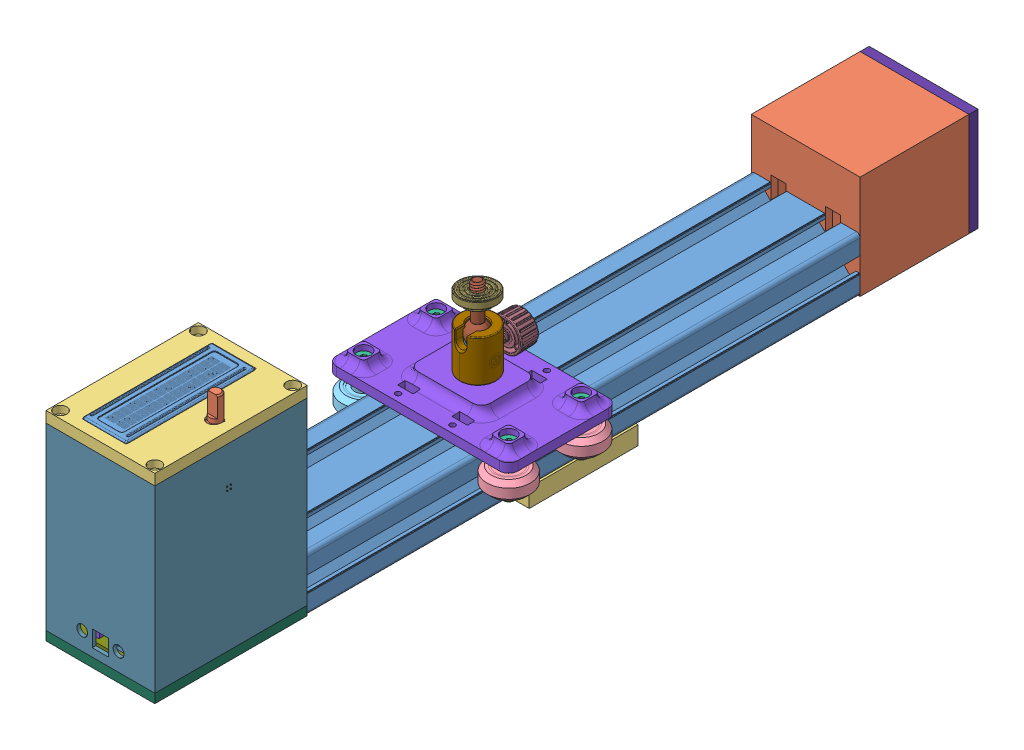
SolidWorks assembly SliderAssembly, configuration Default. Lengths in mm.
Overall size (108.85 134.98 465.23).
58 component instances, 39 part files, 105 mates.
Components (placement in the parent):
- 30x60AluminumExtrusion-1: 30x60AluminumExtrusion [Default] at (105.8219 168.111 384.4079) x (0 -1 0) z (0 0 -1) size (30 60 304.8)
- EndCover-1: EndCover [Default] at (105.8219 170.611 79.6079) x (0 -1 0) z (0 0 -1) size (57 60 60)
- TripodMount-1: TripodMount [Default] at (105.8219 143.111 232.0079) x (0 0 -1) z (0 1 0) size (60 60 10.68)
- VSlotGantryAssembly2-1: VSlotGantryAssembly2 [Default] at (68.2909 143.5962 146.6719) size (108.85 32 72.56)
  - V-Wheel Solid Wheel-1: V-Wheel Solid Wheel [Default] at (76.3282 31.8437 123.3877) x (-0.38895 0 -0.921259) z (-0.921259 0 0.38895) size (23.9 20 23.9)
  - V-Wheel Solid Wheel-2: V-Wheel Solid Wheel [Default] at (87.9897 31.8437 111.6656) x (0.696587 0 0.717472) z (0.717472 0 -0.696587) size (23.9 20 23.9)
  - V-Wheel Solid Wheel - spacer-1: V-Wheel Solid Wheel - spacer [Default] at (-15.7649 31.8437 95.6225) x (-1 0 0) z (0 0 1) size (23.9 17 23.9)
  - V-Wheel Solid Wheel - spacer-2: V-Wheel Solid Wheel - spacer [Default] at (-15.7649 29.8437 135.6225) x (-1 0 0) z (0 0 1) size (23.9 17 23.9)
  - M5x25 low profile screw-1: M5x25 low profile screw [Default] at (-0.4953 49.5148 98.6213) x (1 0 0) z (0 -1 0) size (11 11 27)
  - M5x25 low profile screw-2: M5x25 low profile screw [Default] at (-0.4953 49.5148 138.6213) x (1 0 0) z (0 -1 0) size (11 11 27)
  - M5x25 low profile screw-3: M5x25 low profile screw [Default] at (79.5047 49.5148 98.6213) x (0.999976 0 0.00694) z (0 -1 0) size (11 11 27)
  - M5x25 low profile screw-4: M5x25 low profile screw [Default] at (79.5047 49.5148 138.6213) x (0.999419 0 -0.034076) z (0 -1 0) size (11 11 27)
  - M5 Nylock-1: M5 Nylock [Default] at (-0.4953 25.5148 138.6213) x (-1 0 0) z (0 -1 0) size (8.02 9.26 5)
  - M5 Nylock-2: M5 Nylock [Default] at (-0.4953 27.5148 98.6213) x (-1 0 0) z (0 -1 0) size (8.02 9.26 5)
  - M5 Nylock-3: M5 Nylock [Default] at (79.5047 27.5148 98.6213) x (-1 0 0) z (0 -1 0) size (8.02 9.26 5)
  - M5 Nylock-4: M5 Nylock [Default] at (79.5047 27.5148 138.6213) x (-1 0 0) z (0 -1 0) size (8.02 9.26 5)
  - GantryPlatev2-1: GantryPlatev2 [Default] at (39.5047 42.5148 118.6213) x (-1 0 0) z (0 1 0) size (100 60 10)
- BallHead-1: BallHead [Default] at (109.5949 196.6884 264.1327) size (42.71 44.87 45.01)
  - Ball Head.IGS-1: Ball Head.IGS [Default] at origin size (42.71 44.87 45.01)
    - Gehäuse.IGS-1: Gehäuse.IGS [Default] at origin size (38.01 23.01 20.01)
    - Druckstück.IGS-1: Druckstück.IGS [Default] at (0 -0.5774 0) x (0.996351 0 0.085346) z (-0.085346 0 0.996351) size (23.21 15.61 12)
    - Kugelkopfschraube.IGS-1: Kugelkopfschraube.IGS [Default] at (0 18.5 0) x (0.937202 0.036262 -0.346898) z (0.344349 0.061981 0.936794) size (11.9 30.66 12.01)
    - Scheibe.IGS-1: Scheibe.IGS [Default] at (-0.7516 32.015 -0.6179) x (0.736904 0.071715 0.672182) z (-0.673717 -0.003682 0.73898) size (39.21 6.21 20)
    - Schraube.IGS-1: Schraube.IGS [Default] at (0 9.5 -14.9504) x (0 0 1) z (-0.999799 0.020029 0) size (21.11 18.19 33.94)
- Enclosurev1-5: Enclosurev1 [Default] at (135.8219 232.111 468.4079) x (-1 0 0) z (0 -1 0) size (60 84 99)
- BottomCover-4: BottomCover [Default] at (105.8219 153.111 426.4079) x (0 0 -1) z (0 1 0) size (84 60 5)
- PCB_Assembly-3: PCB_Assembly [Default] at (116.718 142.28 473.9554) x (-1 0 0) z (0 0 -1) size (50 25.86 70)
  - DummyPCB-1: DummyPCB [Default] at (10.8961 19.431 47.5475) x (1 0 0) z (0 -1 0) size (50 75 1.6)
  - ESP32_pinHeader-1: ESP32_pinHeader [Default] at (-11.8439 19.431 67.6769) size (48.76 8 2.5)
  - ESP32_pinHeader-2: ESP32_pinHeader [Default] at (-11.8439 19.431 44.6369) size (48.76 8 2.5)
  - ESP32-1: ESP32 [Default] at (10.8871 26.7106 55.5363) x (0 0 1) z (0 1 0) size (25.55 48.91 13.27)
  - Terminal_2-1: Terminal_2 [Default] at (1.706 19.431 17.5475) x (1 0 0) z (0 1 0) size (10.56 10 18.26)
  - Terminal_2-2: Terminal_2 [Default] at (-8.6851 19.431 17.5475) x (1 0 0) z (0 1 0) size (10.56 10 18.26)
  - PinHeader_5-1: PinHeader_5 [Default] at (-6.1448 19.431 34.2861) size (13.2 8 2.5)
  - PinHeader_2-1: PinHeader_2 [Default] at (8.9821 19.431 34.5153) size (5.58 8 2.5)
  - 0805_resistor-1: 0805_resistor [Default] at (13.7943 19.431 31.1443) size (2 0.6 1.25)
  - PinHeaderMale_4-1: PinHeaderMale_4 [Default] at (1.1821 19.177 37.574) x (-1 0 0) z (0 1 0) size (10.16 2.54 11.94)
  - PinHeaderMale_4-2: PinHeaderMale_4 [Default] at (12.0796 19.177 37.581) x (-1 0 0) z (0 1 0) size (10.16 2.54 11.94)
  - PinHeaderMale_3-1: PinHeaderMale_3 [Default] at (-6.4657 19.431 40.8233) x (1 0 0) z (0 1 0) size (7.62 2.54 11.94)
  - Capacitor2-1: Capacitor2 [Default] at (13.3886 19.421 26.2597) x (0 0 -1) z (0 1 0) size (8.5 8.12 14.12)
  - TMC2209_pinHeader2-1: TMC2209_pinHeader2 [Default] at (32.422 19.431 31.8475) x (0 0 -1) z (1 0 0) size (20.82 8 2.5)
  - TMC2209_pinHeader2-2: TMC2209_pinHeader2 [Default] at (19.722 19.431 31.8475) x (0 0 -1) z (1 0 0) size (20.82 8 2.5)
  - TMC2209-2: TMC2209 [Default] at (26.072 27.151 22.8475) x (0 0 1) z (0 1 0) size (20.6 15.43 22.6)
- BeltTensionerAssembly-2: BeltTensionerAssembly [Default] at (123.7274 141.4711 84.1198) x (-0.8441 0 0.536186) z (-0.536186 0 -0.8441) size (64.72 49 62.26)
  - SliderPlate-1: SliderPlate [Default] at (-6.0834 22.0445 41.5251) x (-0.8441 0 -0.536186) z (0 1 0) size (50 20 34)
  - BasePlate-2: BasePlate [Default] at (-6.7261 16.0445 42.537) x (0.8441 0 0.536186) z (0 1 0) size (50 40 6)
  - FrontFixed-2: FrontFixed [Default] at (-15.5732 22.0445 56.4646) x (0.8441 0 0.536186) z (0 1 0) size (50 42 11)
  - washer-1: washer [Default] at (-6.0834 50.0445 41.5251) x (0 0 1) z (0 -1 0) size (8 8 1)
  - washer-2: washer [Default] at (-6.0834 34.0445 41.5251) x (1 0 0) z (0 -1 0) size (8 8 1)
  - M5x25-1: M5x25 [Default] at (-6.0834 65.0445 41.5251) x (0 -1 0) z (0 0 1) size (35 7 7)
  - ideler-1: ideler [Default] at (-6.0834 49.0445 41.5251) x (0 -1 0) z (-1 0 0) size (15 32 32)
- endCover-connect-1: endCover-connect [Default] at (90.8219 168.111 79.6079) size (8.7 8.7 20)
- endCover-connect-2: endCover-connect [Default] at (120.8219 168.111 79.6079) x (-0.035719 0.999362 0) z (0 0 1) size (8.7 8.7 20)
- Logo-3: Logo [Default] at (105.8219 181.611 14.6079) size (60 57 6)
- Nema17-3: Nema17 [По умолчанию] at (105.9877 241.111 427.2351) x (-0.021334 0 0.999772) z (0.999772 0 0.021334) size (42.3 62 51.35)
- LCD-1: LCD [Default] at (101.4719 257.111 426.7579) x (0 0 1) z (-1 0 0) size (80.2 17.64 36)
- Rotary_Encoder-1: Rotary_Encoder [Default] at (129.8687 248.411 427.8198) x (-1 0 0) z (0 1 0) size (19 32 30)
- TopCover-5: TopCover [Default] at (105.8219 257.111 428.4079) x (0 0 -1) z (0 1 0) size (84 60 6)
Mates (geometry in assembly coordinates):
- Concentric1: concentric aligned: cylinder of Nema17-1 through (105.8219 169.111 424.4079) axis (0 1 0) radius 2.5; cylinder of GT2TimingPulley-1 through (105.8219 170.311 424.4079) axis (0 1 0) radius 2.5
- Coincident4: coincident aligned: plane of Nema17-1 through (105.8219 169.111 424.4079) normal (0 -1 0); plane of GT2TimingPulley-1 through (105.8219 169.111 424.4079) normal (0 -1 0)
- Distance7: distance = 0 mm anti-aligned: plane of VSlotGantryAssembly-1/80mm gantry plate-1 through (103.8719 183.111 236.703) normal (0 -1 0); plane of 30x60AluminumExtrusion-1 through (95.3219 183.111 79.6079) normal (0 1 0)
- Tangent1: tangent anti-aligned: plane of 30x60AluminumExtrusion-1 through (75.8219 181.079 79.6079) normal (-1 0 0); cylinder of VSlotGantryAssembly-1/V-Wheel Solid Wheel-2 through (63.8719 171.226 206.703) axis (0 -1 0) radius 11.95
- Tangent2: tangent anti-aligned: plane of 30x60AluminumExtrusion-1 through (75.8219 181.079 79.6079) normal (-1 0 0); cylinder of VSlotGantryAssembly-1/V-Wheel Solid Wheel-1 through (63.8719 171.226 266.703) axis (0 -1 0) radius 11.95
- Coincident30: coincident aligned: plane of 30x60AluminumExtrusion-1 through (75.8219 155.143 79.6079) normal (-1 0 0); plane of EndCover-1 through (75.8219 198.111 19.6079) normal (-1 0 0)
- Coincident31: coincident aligned: plane of 30x60AluminumExtrusion-1 through (95.3219 153.111 79.6079) normal (0 -1 0); plane of EndCover-1 through (135.8219 153.111 19.6079) normal (0 -1 0)
- Coincident32: coincident anti-aligned: plane of 30x60AluminumExtrusion-1 through (77.8539 181.079 79.6079) normal (0 0 -1); plane of EndCover-1 through (105.8219 170.611 79.6079) normal (0 0 1)
- Distance8: distance = 12.5 mm aligned: plane of Logo-1 through (57.6023 165.611 2.2147) normal (0 -1 0); plane of EndCover-1 through (135.8219 153.111 19.6079) normal (0 -1 0)
- Coincident37: coincident anti-aligned: plane of EndCover-1 through (131.5466 154.5156 77.6079) normal (0 1 0); plane of BeltTensionerAssembly-2/BasePlate-1 through (104.5466 154.5156 52.6079) normal (0 -1 0)
- Coincident38: coincident anti-aligned: plane of EndCover-1 through (105.8219 170.611 75.6079) normal (0 0 -1); plane of BeltTensionerAssembly-2/BasePlate-1 through (79.5466 154.5156 77.6079) normal (0 0 1)
- Distance9: distance = 5 mm anti-aligned: plane of BeltTensionerAssembly-2/BasePlate-1 through (129.5466 154.5156 27.6079) normal (1 0 0); plane of EndCover-1 through (134.5466 157.5156 77.6079) normal (-1 0 0)
- Tangent3: tangent anti-aligned: plane of ? through (103.8719 186.111 236.703) normal (0 1 0); face of ?
- Coincident47: coincident aligned: plane of 30x60AluminumExtrusion-1 through (75.8219 155.143 79.6079) normal (-1 0 0); plane of TripodMount-1 through (75.8219 153.111 262.0079) normal (-1 0 0)
- Coincident48: coincident anti-aligned: plane of 30x60AluminumExtrusion-1 through (95.3219 153.111 79.6079) normal (0 -1 0); plane of TripodMount-1 through (105.8219 153.111 232.0079) normal (0 1 0)
- Distance10: distance = 122.4 mm anti-aligned: plane of TripodMount-1 through (135.8219 153.111 202.0079) normal (0 0 -1); plane of EndCover-1 through (105.8219 170.611 79.6079) normal (0 0 1)
- Coincident50: coincident aligned: plane of 30x60AluminumExtrusion-1 through (135.8219 181.079 79.6079) normal (1 0 0); plane of Enclosurev1-3 through (135.8219 157.111 464.4079) normal (1 0 0)
- Concentric2: concentric aligned: cylinder of 30x60AluminumExtrusion-1 through (120.8219 168.111 79.6079) axis (0 0 1) radius 3.5; cylinder of Enclosurev1-3 through (120.8219 168.111 369.4079) axis (0 0 1) radius 3.5
- Coincident51: coincident anti-aligned: plane of 30x60AluminumExtrusion-1 through (77.8539 181.079 384.4079) normal (0 0 1); plane of Enclosurev1-3 through (135.8219 157.111 384.4079) normal (0 0 -1)
- Distance11: distance = 3 mm anti-aligned: plane of PCB_Assembly-1/DummyPCB-1 through (84.0424 153.111 395.4079) normal (0 -1 0); plane of BottomCover-1 through (132.8219 157.111 387.4079) normal (0 1 0)
- Distance12: distance = 5 mm aligned: plane of PCB_Assembly-1/DummyPCB-1 through (81.0424 153.111 459.4079) normal (-1 0 0); plane of BottomCover-1 through (55.8219 157.111 441.4079) normal (-1 0 0)
- Coincident56: coincident anti-aligned: plane of Enclosurev1-3 through (133.8219 239.111 462.4079) normal (0 0 -1); plane of PCB_Assembly-1/DummyPCB-1 through (128.0424 153.111 462.4079) normal (0 0 1)
- Coincident57: coincident aligned: plane of Enclosurev1-3 through (135.8219 239.111 464.4079) normal (0 1 0); plane of OLED-1 through (149.8219 227.611 435.6192) normal (0 1 0)
- Coincident58: coincident aligned: plane of Enclosurev1-3 through (135.8219 239.111 387.4079) normal (0 0 -1); plane of OLED-1 through (156.71 238.111 387.4079) normal (0 0 -1)
- Coincident60: coincident aligned: plane of Enclosurev1-3 through (135.8219 239.111 464.4079) normal (0 1 0); plane of OLED-2 through (149.8219 228.111 435.6192) normal (0 1 0)
- Coincident61: coincident anti-aligned: plane of Enclosurev1-3 through (162.8219 216.111 389.4079) normal (0 0 1); plane of OLED-2 through (145.023 238.111 389.4079) normal (0 0 -1)
- Coincident62: coincident aligned: circle of Enclosurev1-3; plane of Rotary_Encoder-2 through (154.746 237.111 450.1435) normal (0 1 0)
- Coincident63: coincident aligned: circle of Enclosurev1-3; plane of Rotary_Encoder-3 through (152.0684 237.111 430.2318) normal (0 1 0)
- Coincident64: coincident: plane of Enclosurev1-3 through (162.8219 239.111 444.4079) normal (-1 0 0); line of Rotary_Encoder-3 through (162.8219 223.286 438.5345) axis (0 0 -1)
- Coincident65: coincident aligned: plane of 30x60AluminumExtrusion-1 through (135.8219 181.079 79.6079) normal (1 0 0); plane of Enclosurev1-4 through (135.8219 153.111 464.4079) normal (1 0 0)
- Coincident66: coincident aligned: plane of 30x60AluminumExtrusion-1 through (125.3219 153.111 79.6079) normal (0 -1 0); plane of Enclosurev1-4 through (135.8219 153.111 464.4079) normal (0 -1 0)
- Coincident67: coincident anti-aligned: plane of 30x60AluminumExtrusion-1 through (77.8539 181.079 384.4079) normal (0 0 1); plane of Enclosurev1-4 through (135.8219 153.111 384.4079) normal (0 0 -1)
- Coincident68: coincident aligned: plane of Enclosurev1-4 through (135.8219 153.111 464.4079) normal (1 0 0); plane of TopCover-2 through (135.8219 231.111 461.4079) normal (1 0 0)
- Coincident69: coincident aligned: plane of Enclosurev1-4 through (135.8219 153.111 384.4079) normal (0 0 -1); plane of TopCover-2 through (78.8219 231.111 384.4079) normal (0 0 -1)
- Coincident70: coincident anti-aligned: plane of Enclosurev1-4 through (135.8219 231.111 464.4079) normal (0 1 0); plane of TopCover-2 through (78.8219 231.111 461.4079) normal (0 -1 0)
- Coincident71: coincident anti-aligned: plane of Nema17-1 through (105.8219 231.111 424.4079) normal (0 1 0); plane of TopCover-2 through (78.8219 231.111 461.4079) normal (0 -1 0)
- Concentric4: concentric anti-aligned: circle of Nema17-1; circle of TopCover-2
- Coincident72: coincident aligned: plane of Enclosurev1-4 through (135.8219 153.111 464.4079) normal (1 0 0); plane of BottomCover-2 through (135.8219 153.111 387.4079) normal (1 0 0)
- Coincident74: coincident anti-aligned: plane of Enclosurev1-4 through (135.8219 153.111 464.4079) normal (0 -1 0); plane of BottomCover-2 through (132.8219 153.111 461.4079) normal (0 1 0)
- Coincident75: coincident aligned: plane of Enclosurev1-4 through (135.8219 153.111 464.4079) normal (0 0 1); plane of BottomCover-2 through (78.8219 153.111 464.4079) normal (0 0 1)
- Coincident76: coincident aligned: plane of PCB_Assembly-1/DummyPCB-1 through (84.0424 153.111 395.4079) normal (0 -1 0); plane of Enclosurev1-4 through (135.8219 153.111 464.4079) normal (0 -1 0)
- Coincident77: coincident anti-aligned: plane of PCB_Assembly-1/DummyPCB-1 through (128.0424 153.111 462.4079) normal (0 0 1); plane of Enclosurev1-4 through (133.8219 231.111 462.4079) normal (0 0 -1)
- Coincident79: coincident anti-aligned: plane of Enclosurev1-4 through (149.9219 218.111 399.4579) normal (0 0 1); plane of OLED-1 through (149.9219 227.611 399.4579) normal (0 0 -1)
- Coincident80: coincident anti-aligned: plane of Enclosurev1-4 through (149.9219 218.111 430.6479) normal (1 0 0); plane of OLED-1 through (149.9219 227.611 430.6496) normal (-1 0 0)
- Distance13: distance = 0.5 mm aligned: plane of OLED-1 through (149.8219 227.611 435.6192) normal (0 1 0); plane of Enclosurev1-4 through (175.8219 228.111 461.4079) normal (0 1 0)
- Distance14: distance = 2 mm anti-aligned: plane of VSlotGantryAssembly2-1/BasePlateGantry-1 through (45.3719 185.111 289.6019) normal (0 -1 0); plane of 30x60AluminumExtrusion-1 through (95.3219 183.111 79.6079) normal (0 1 0)
- Tangent6: tangent anti-aligned: plane of ? through (45.3719 190.111 289.6019) normal (0 1 0); edge_curve of ?
- Tangent9: tangent aligned: cylinder of ? through (103.8719 190.111 328.6019) axis (0 -1 0) radius 3; edge_curve of ?
- Coincident84: coincident aligned: plane of 30x60AluminumExtrusion-1 through (135.8219 155.143 79.6079) normal (1 0 0); plane of Enclosurev1-5 through (135.8219 257.111 468.4079) normal (1 0 0)
- Coincident85: coincident anti-aligned: plane of 30x60AluminumExtrusion-1 through (77.8539 181.079 384.4079) normal (0 0 1); plane of Enclosurev1-5 through (135.8219 257.111 384.4079) normal (0 0 -1)
- Coincident86: coincident aligned: plane of Enclosurev1-5 through (135.8219 257.111 384.4079) normal (0 0 -1); plane of TopCover-3 through (132.8219 272.111 384.4079) normal (0 0 -1)
- Coincident87: coincident aligned: plane of Enclosurev1-5 through (135.8219 257.111 468.4079) normal (1 0 0); plane of TopCover-3 through (135.8219 272.111 384.4079) normal (1 0 0)
- Coincident88: coincident anti-aligned: plane of Enclosurev1-5 through (135.8219 257.111 468.4079) normal (0 1 0); plane of TopCover-3 through (105.8219 266.111 428.4079) normal (0 -1 0)
- Coincident89: coincident aligned: plane of Enclosurev1-5 through (135.8219 257.111 468.4079) normal (1 0 0); plane of BottomCover-3 through (135.8219 153.111 387.4079) normal (1 0 0)
- Coincident90: coincident aligned: plane of Enclosurev1-5 through (135.8219 257.111 468.4079) normal (0 0 1); plane of BottomCover-3 through (78.8219 153.111 464.4079) normal (0 0 1)
- Coincident91: coincident anti-aligned: plane of Enclosurev1-5 through (135.8219 153.111 464.4079) normal (0 -1 0); plane of BottomCover-3 through (132.8219 153.111 461.4079) normal (0 1 0)
- Coincident95: coincident anti-aligned: plane of TopCover-3 through (105.8219 266.111 428.4079) normal (0 -1 0); plane of Nema17-2 through (105.8219 266.111 424.4079) normal (0 1 0)
- Coincident99: coincident: plane of BottomCover-4 through (105.8219 158.111 426.4079) normal (0 1 0); plane of PCB_Assembly-2/DummyPCB-1 through (130.8219 157.111 434.7398) normal (0 -1 0)
- Distance15: distance = 2 mm aligned: plane of PCB_Assembly-2/DummyPCB-1 through (133.8219 157.111 478.7398) normal (1 0 0); plane of BottomCover-4 through (135.8219 158.111 387.4079) normal (1 0 0)
- Concentric7: concentric aligned: cylinder of Nema17-2 through (105.8219 204.111 424.4079) axis (0 1 0) radius 2.5; cylinder of GT2TimingPulley-2 through (105.8219 170.311 424.4079) axis (0 1 0) radius 2.5
- Coincident102: coincident aligned: plane of Nema17-2 through (105.8219 204.111 424.4079) normal (0 -1 0); plane of GT2TimingPulley-2 through (105.8219 169.111 424.4079) normal (0 -1 0)
- Coincident103: coincident anti-aligned: plane of Enclosurev1-5 through (161.7219 218.111 399.4579) normal (-1 0 0); plane of OLED-2 through (161.7219 228.111 430.6496) normal (1 0 0)
- Coincident104: coincident anti-aligned: plane of Enclosurev1-5 through (149.9219 218.111 399.4579) normal (0 0 1); plane of OLED-2 through (149.9219 228.111 399.4579) normal (0 0 -1)
- Coincident105: coincident aligned: plane of Enclosurev1-5 through (175.8219 228.111 461.4079) normal (0 1 0); plane of OLED-2 through (149.8219 228.111 435.6192) normal (0 1 0)
- Coincident106: coincident anti-aligned: plane of EndCover-1 through (131.5466 154.5156 77.6079) normal (0 1 0); plane of BeltTensionerAssembly-1/BasePlate-2 through (105.6257 154.5156 57.6079) normal (0 -1 0)
- Coincident107: coincident anti-aligned: plane of EndCover-1 through (105.8219 170.611 75.6079) normal (0 0 -1); plane of BeltTensionerAssembly-1/BasePlate-2 through (130.6257 160.5156 77.6079) normal (0 0 1)
- Distance17: distance = 5 mm aligned: plane of EndCover-1 through (105.8219 170.611 19.6079) normal (0 0 -1); plane of BeltTensionerAssembly-2/BasePlate-2 through (131.5972 163.5156 24.6079) normal (0 0 -1)
- Coincident113: coincident anti-aligned: plane of EndCover-1 through (105.8219 157.5156 75.6079) normal (0 1 0); plane of BeltTensionerAssembly-2/BasePlate-2 through (106.5972 157.5156 44.6079) normal (0 -1 0)
- Coincident114: coincident anti-aligned: plane of EndCover-1 through (81.5972 157.5156 78.4363) normal (1 0 0); plane of BeltTensionerAssembly-2/BasePlate-2 through (81.5972 163.5156 24.6079) normal (-1 0 0)
- Concentric8: concentric aligned: cylinder of EndCover-1 through (120.8219 168.111 85.1233) axis (0 0 -1) radius 1.95; cylinder of endCover-connect-2 through (120.8219 168.111 99.6079) axis (0 0 -1) radius 1.95
- Coincident115: coincident anti-aligned: plane of EndCover-1 through (105.8219 170.611 79.6079) normal (0 0 1); plane of endCover-connect-2 through (120.8219 168.111 79.6079) normal (0 0 -1)
- Coincident116: coincident anti-aligned: plane of EndCover-1 through (105.8219 170.611 79.6079) normal (0 0 1); plane of endCover-connect-1 through (90.8219 168.111 79.6079) normal (0 0 -1)
- Concentric9: concentric aligned: cylinder of EndCover-1 through (90.8219 168.111 85.1233) axis (0 0 -1) radius 1.95; cylinder of endCover-connect-1 through (90.8219 168.111 99.6079) axis (0 0 -1) radius 1.95
- Coincident117: coincident: plane of EndCover-1 through (75.8219 198.111 19.6079) normal (-1 0 0); plane of Logo-2 through (75.8219 149.1968 19.6079) normal (-1 0 0)
- Coincident118: coincident aligned: plane of EndCover-1 through (105.8219 170.611 19.6079) normal (0 0 -1); plane of Logo-2 through (104.3219 179.1968 19.6079) normal (0 0 -1)
- Coincident119: coincident anti-aligned: plane of EndCover-1 through (105.8219 170.611 19.6079) normal (0 0 -1); plane of Logo-3 through (105.8219 181.611 19.6079) normal (0 0 1)
- Coincident120: coincident aligned: plane of EndCover-1 through (135.8219 188.111 19.6079) normal (1 0 0); plane of Logo-3 through (135.8219 153.111 19.6079) normal (1 0 0)
- Coincident121: coincident aligned: plane of EndCover-1 through (135.8219 153.111 19.6079) normal (0 -1 0); plane of Logo-3 through (75.8219 153.111 19.6079) normal (0 -1 0)
- Parallel1: parallel anti-aligned: plane of EndCover-1 through (105.8219 170.611 19.6079) normal (0 0 -1); plane of Logo-3 through (105.8219 181.611 19.6079) normal (0 0 1)
- Coincident123: coincident aligned: plane of TopCover-4 through (105.8219 262.111 424.4079) normal (0 1 0); plane of LCD-1 through (101.4719 264.111 426.7579) normal (0 1 0)
- Coincident126: coincident anti-aligned: plane of Rotary_Encoder-1 through (126.3219 250.161 429.1517) normal (0 1 0); plane of TopCover-4 through (105.8219 256.111 424.4079) normal (0 -1 0)
- Coincident129: coincident: line of Rotary_Encoder-1 through (135.8219 249.286 442.4017) axis (0 0 -1); plane of TopCover-4 through (135.8219 256.111 468.4079) normal (1 0 0)
- Coincident130: coincident aligned: plane of Enclosurev1-5 through (135.8219 257.111 468.4079) normal (1 0 0); plane of TopCover-4 through (135.8219 256.111 468.4079) normal (1 0 0)
- Coincident133: coincident anti-aligned: plane of Enclosurev1-5 through (135.8219 257.111 468.4079) normal (0 1 0); plane of TopCover-4 through (105.8219 256.111 424.4079) normal (0 -1 0)
- Coincident134: coincident aligned: plane of Enclosurev1-5 through (135.8219 257.111 468.4079) normal (1 0 0); plane of TopCover-4 through (135.8219 256.111 468.4079) normal (1 0 0)
- Coincident135: coincident aligned: plane of Enclosurev1-5 through (135.8219 257.111 468.4079) normal (0 0 1); plane of TopCover-4 through (132.8219 256.111 468.4079) normal (0 0 1)
- Tangent12: tangent: circle of Rotary_Encoder-1; cylinder of TopCover-4 through (128.8219 180.2163 426.4079) axis (0 1 0) radius 3.6
- Coincident136: coincident anti-aligned: plane of Enclosurev1-5 through (135.8219 201.111 528.5411) normal (0 1 0); plane of Nema17-3 through (105.9877 201.111 427.2351) normal (0 -1 0)
- Concentric10: concentric aligned: cylinder of Enclosurev1-5 through (90.8219 192.5855 411.4079) axis (0 1 0) radius 1.6; cylinder of Nema17-3 through (90.8219 201.111 411.4079) axis (0 1 0) radius 1.25
- Coincident137: coincident anti-aligned: plane of LCD-1 through (101.4719 257.111 426.7579) normal (0 1 0); plane of TopCover-5 through (105.8219 257.111 428.4079) normal (0 -1 0)
- Coincident138: coincident anti-aligned: plane of LCD-1 through (89.8219 181.7838 462.4079) normal (0 0 1); plane of TopCover-5 through (89.8219 339.0057 462.4079) normal (0 0 -1)
- Coincident139: coincident anti-aligned: plane of LCD-1 through (89.8219 181.7838 391.1079) normal (-1 0 0); plane of TopCover-5 through (89.8219 339.0057 426.4079) normal (1 0 0)
- Coincident141: coincident: line of Rotary_Encoder-1 through (135.8219 249.286 442.4017) axis (0 0 -1); plane of TopCover-5 through (135.8219 263.111 384.4079) normal (1 0 0)
- Coincident143: coincident anti-aligned: plane of Enclosurev1-5 through (135.8219 257.111 468.4079) normal (0 1 0); plane of TopCover-5 through (105.8219 257.111 428.4079) normal (0 -1 0)
- Coincident144: coincident aligned: plane of Enclosurev1-5 through (135.8219 257.111 468.4079) normal (0 0 1); plane of TopCover-5 through (135.8219 263.111 468.4079) normal (0 0 1)
- Coincident145: coincident aligned: plane of Enclosurev1-5 through (135.8219 257.111 468.4079) normal (1 0 0); plane of TopCover-5 through (135.8219 263.111 384.4079) normal (1 0 0)
- Coincident146: coincident aligned: plane of Rotary_Encoder-1 through (127.5192 263.111 426.6552) normal (0 1 0); plane of TopCover-5 through (105.8219 263.111 428.4079) normal (0 1 0)
- Distance18: distance = 2 mm anti-aligned: plane of PCB_Assembly-3/DummyPCB-1 through (83.8219 160.111 391.9079) normal (0 -1 0); plane of BottomCover-4 through (105.8219 158.111 426.4079) normal (0 1 0)
- Concentric11: concentric aligned: cylinder of BottomCover-4 through (83.8219 155.111 460.9079) axis (0 1 0) radius 1.5; cylinder of PCB_Assembly-3/DummyPCB-1 through (83.8219 160.111 460.9079) axis (0 1 0) radius 1.5
- Concentric12: concentric aligned: cylinder of BottomCover-4 through (127.8219 155.111 460.9079) axis (0 1 0) radius 1.5; cylinder of PCB_Assembly-3/DummyPCB-1 through (127.8219 160.111 460.9079) axis (0 1 0) radius 1.5
- Coincident149: coincident anti-aligned: plane of Enclosurev1-5 through (-10.4961 158.111 384.4079) normal (0 -1 0); plane of BottomCover-4 through (105.8219 158.111 426.4079) normal (0 1 0)
- Coincident150: coincident aligned: plane of Enclosurev1-5 through (135.8219 257.111 468.4079) normal (1 0 0); plane of BottomCover-4 through (135.8219 158.111 387.4079) normal (1 0 0)
- Coincident151: coincident aligned: plane of Enclosurev1-5 through (135.8219 257.111 468.4079) normal (0 0 1); plane of BottomCover-4 through (132.8219 158.111 468.4079) normal (0 0 1)
- Distance19: distance = 3 mm anti-aligned: plane of VSlotGantryAssembly2-1/GantryPlatev2-1 through (62.7956 186.111 290.2931) normal (0 -1 0); plane of 30x60AluminumExtrusion-1 through (86.3219 183.111 79.6079) normal (0 1 0)
- Tangent14: tangent anti-aligned: plane of VSlotGantryAssembly2-1/GantryPlatev2-1 through (92.7956 196.111 275.2931) normal (0 1 0); edge_curve of BallHead-1/Ball Head.IGS-1/Druckstück.IGS-1
